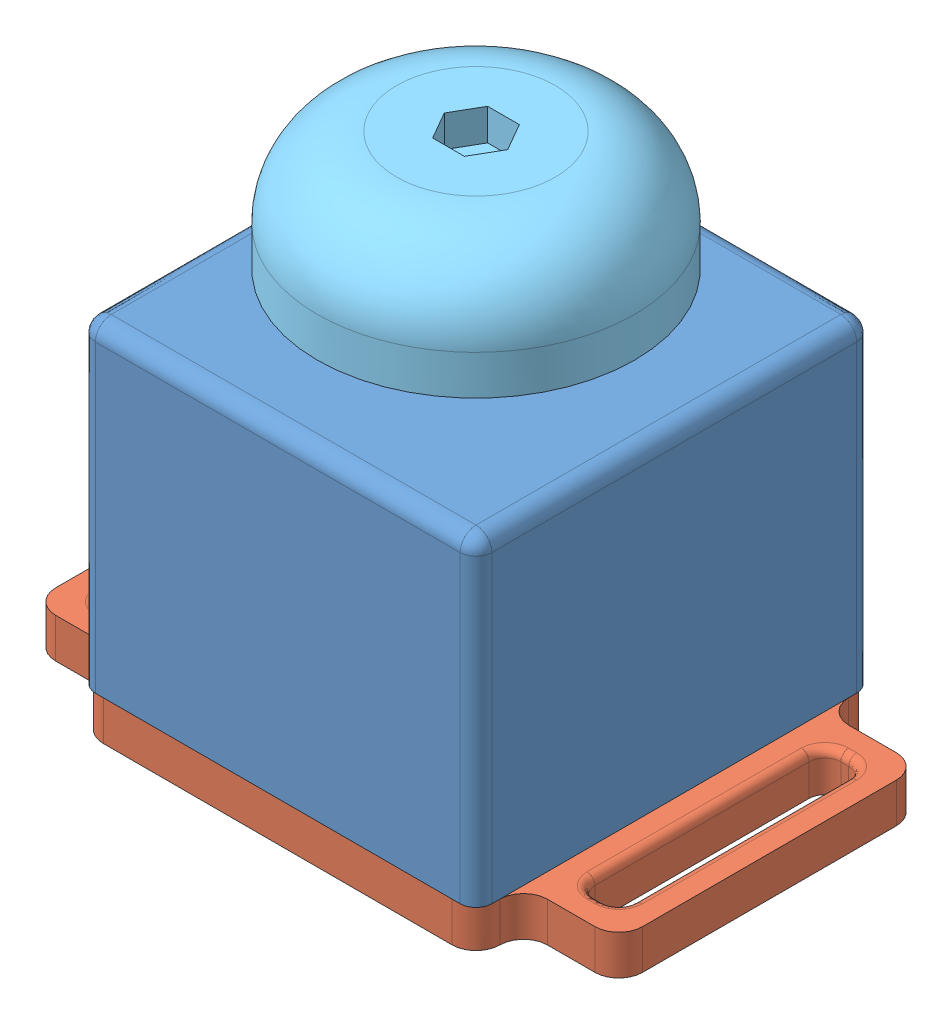
SolidWorks assembly boton de segurança, configuration Default. Lengths in mm.
Overall size (74 65.35 50).
6 component instances, 6 part files, 13 mates.
Components (placement in the parent):
- caja-1: caja [Default] at (-66.1118 -55.9787 49.3767) size (50 40.35 50)
- base-1: base [Default] at (-66.1118 -51.3287 49.3767) size (74 28 50)
- botao-1: botao [Default] at (-66.1118 -36.3287 49.3767) size (18.4 27.02 15.96)
- base boton-1: base boton [Default] at (-66.1118 -12.9787 49.3767) size (30 13.3 36)
- base boton sup-1: base boton sup [Default] at (-66.1118 3.0213 49.3767) size (40 15 40)
- base boton 2-1: base boton 2 [Default] at (-66.1118 -12.9787 49.3767) size (21.5 15 19.5)
Mates (geometry in assembly coordinates):
- Coincident2: coincident: plane of assembly; plane of assembly; plane of caja-1 through (-91.1118 -5.9787 24.3767) normal (0 0 -1); plane of base-1 through (-88.1118 -46.3287 24.3767) normal (0 0 -1)
- Concentric1: concentric: cylinder of assembly; cylinder of assembly; cylinder of base-1 through (-66.1118 -46.4287 49.3767) axis (0 1 0) radius 8; cylinder of botao-1 through (-66.1118 -15.9787 49.3767) axis (0 -1 0) radius 3.95
- Distance1: distance = 10 mm: plane of assembly; plane of assembly; plane of botao-1 through (-66.1118 -36.3287 49.3767) normal (0 -1 0); plane of base-1 through (-88.1118 -46.3287 71.3767) normal (0 1 0)
- Distance3: distance = 5 mm: plane of assembly; plane of assembly; plane of caja-1 through (-66.1118 -5.9787 49.3767) normal (0 1 0); plane of base boton sup-1 through (-66.1118 -0.9787 49.3767) normal (0 -1 0)
- Concentric4: concentric: cylinder of ? through (-72.6118 -13.9787 49.3767) axis (0 1 0) radius 1; cylinder of ? through (-72.6118 -3.9787 49.3767) axis (0 -1 0) radius 1
- Concentric5: concentric: cylinder of ? through (-66.1118 -7.9787 49.3767) axis (0 -1 0) radius 4.1; cylinder of ? through (-66.1118 -7.9787 49.3767) axis (0 -1 0) radius 4.1
- Coincident5: coincident: plane of ? through (-66.1118 -8.9787 49.3767) normal (0 1 0); plane of ? through (-87.4127 -8.9787 31.3767) normal (0 -1 0)
- Concentric6: concentric: cylinder of botao-1 through (-66.1118 -15.9787 49.3767) axis (0 -1 0) radius 3.95; cylinder of ? through (-66.1118 -7.9787 49.3767) axis (0 -1 0) radius 4.1
- Distance4: distance = 0.2 mm: plane of ? through (-66.1118 -22.2787 49.3767) normal (0 -1 0); plane of botao-1 through (-66.1118 -22.4787 49.3767) normal (0 1 0)
- Parallel3: parallel: plane of caja-1 through (-91.1118 -5.9787 74.3767) normal (-1 0 0); plane of ? through (-76.862 -0.9787 47.6767) normal (-1 0 0)
- Coincident6: coincident: plane of assembly; plane of assembly; plane of caja-1 through (-41.1118 -46.3287 74.3767) normal (0 -1 0); plane of base-1 through (-88.1118 -46.3287 71.3767) normal (0 1 0)
- Concentric7: concentric: cylinder of base boton sup-1 through (-66.1118 -0.9787 49.3767) axis (0 1 0) radius 9.75; cylinder of ? through (-66.1118 3.0213 49.3767) axis (0 -1 0) radius 9.75
- Parallel4: parallel: plane of base boton sup-1 through (-67.7421 6.0213 44.9602) normal (1 0 0); plane of ? through (-76.862 -0.9787 47.6767) normal (-1 0 0)
